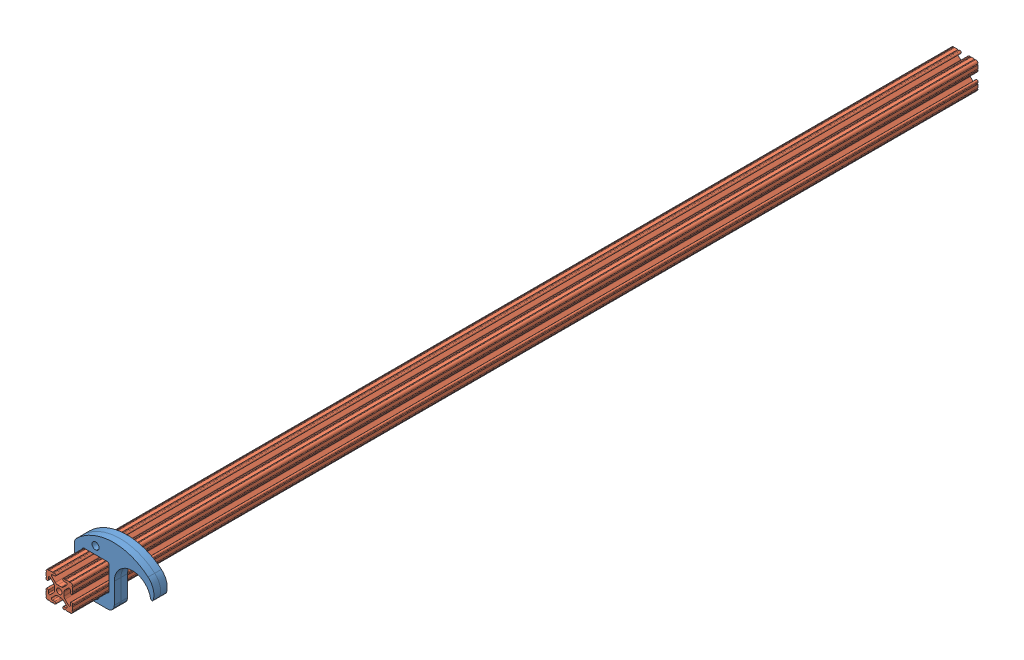
SolidWorks assembly 2018-507-A, configuration Default. Lengths in mm.
Overall size (75.94 57.91 863.6).
3 component instances, 2 part files, 5 mates.
Components (placement in the parent):
- 2018-507-D001-1: 2018-507-D001 [Default] at origin size (75.94 57.91 6.35)
- 2018-507-D001-2: 2018-507-D001 [Default] at (0 0 6.35) size (75.94 57.91 6.35)
- 2018-500-D003-1: 2018-500-D003 [Default] at (-35.3219 0 -368.6675) size (25.4 25.4 863.6)
Mates (geometry in assembly coordinates):
- Coincident1: coordinate: point of 2018-507-D001-1; point of assembly
- Concentric1: concentric aligned: cylinder of 2018-507-D001-1 through (-35.3219 20.32 -3.175) axis (0 0 1) radius 3.3782; cylinder of 2018-507-D001-2 through (-35.3219 20.32 3.175) axis (0 0 1) radius 3.3782
- Coincident2: coincident anti-aligned: plane of 2018-507-D001-1 through (0 0 3.175) normal (0 0 1); plane of 2018-507-D001-2 through (0 0 3.175) normal (0 0 -1)
- Parallel1: parallel aligned: plane of 2018-507-D001-2 through (0 0 6.35) normal (0 1 0); plane of assembly through (0 0 0) normal (0 1 0)
- Coincident3: coincident aligned: plane of 2018-500-D003-1 through (-35.3219 0 -368.6675) normal (0 1 0); plane of assembly through (0 0 0) normal (0 1 0)
